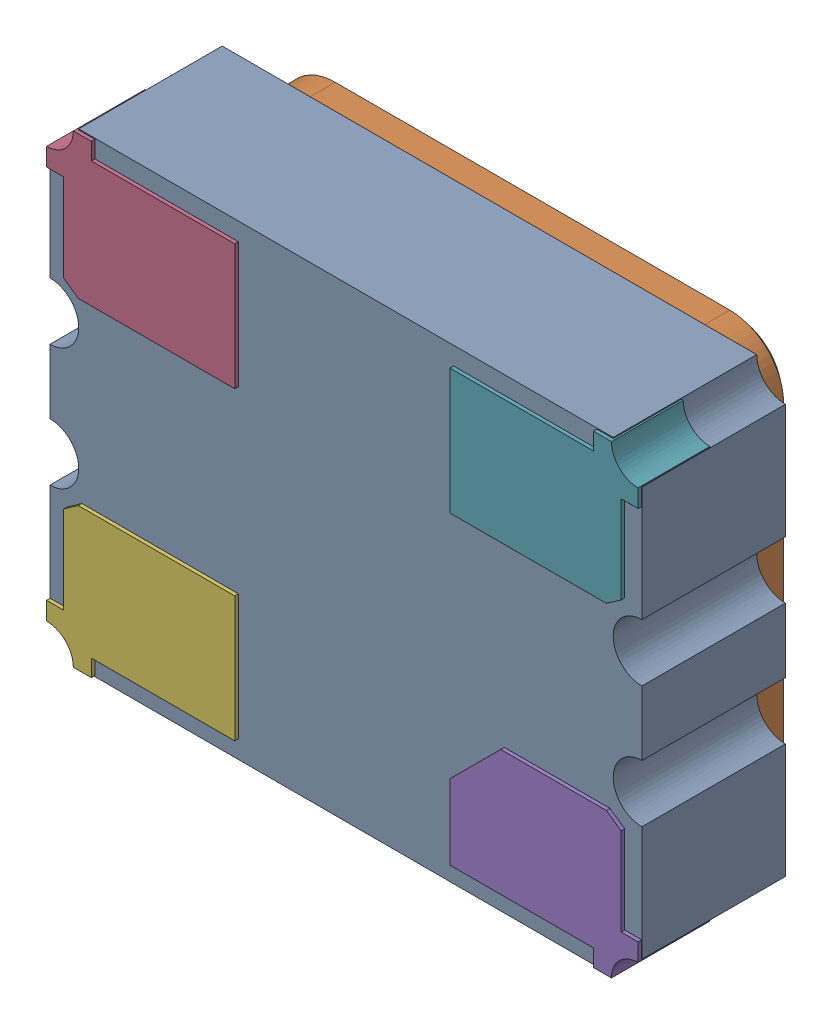
SolidWorks assembly Y1摄像头, configuration 默认. Lengths in mm.
Overall size (3.3 2.6 1.1).
5 component instances, 4 part files, 0 mates.
Components (placement in the parent):
- XTAL-OSC-3225-1: XTAL-OSC-3225 [默认] at (0.2033 4.7751 -0.3912) x (1 0 0) z (0 0 -1) size (3.3 2.6 1.1)
  - User_Library-ASTX-H11_Pad-1: User_Library-ASTX-H11_Pad [默认] at origin size (3.3 2.6 0.8)
  - User_Library-ASTX-H11_Pad001-1: User_Library-ASTX-H11_Pad001 [默认] at origin size (2.8 2.4 0.24)
  - User_Library-ASTX-H11_Pad002-1: User_Library-ASTX-H11_Pad002 [默认] at origin size (2.7 2.3 0.04)
  - User_Library-ASTX-H11_ComponentPads-1: User_Library-ASTX-H11_ComponentPads [默认] at origin size (3.3 2.59 0.4)
